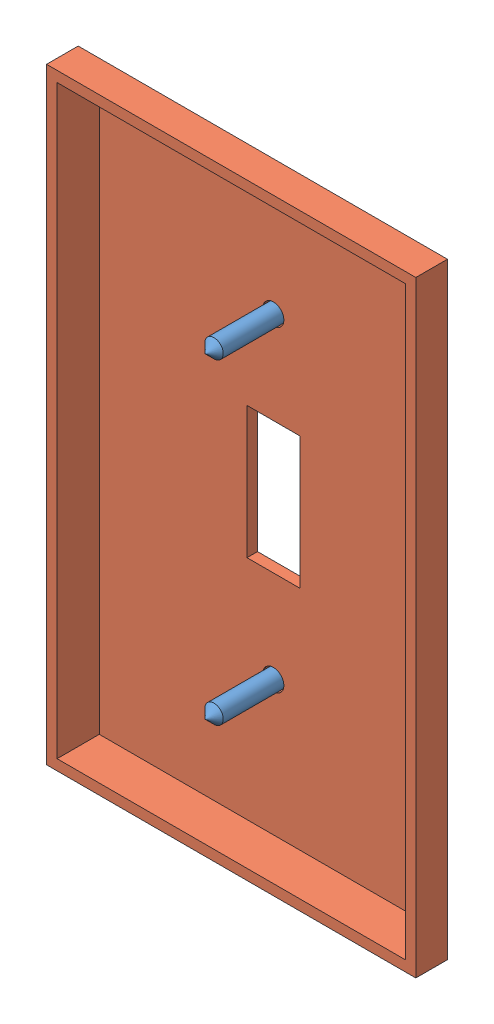
SolidWorks assembly 8.2, configuration Default. Lengths in mm.
Overall size (70 115 18.07).
3 component instances, 2 part files, 4 mates.
Components (placement in the parent):
- fastener-1: fastener [Default] at (7.1613 18.208 7.5946) size (8 8 18.07)
- exercise2.2-1: exercise2.2 [Default] at (-27.8387 -9.292 10.5946) x (1 0 0) z (0 -1 0) size (70 10 115)
- fastener-2: fastener [Default] at (7.1613 78.208 7.5946) size (8 8 18.07)
Mates (geometry in assembly coordinates):
- Concentric1: concentric anti-aligned: cylinder of exercise2.2-1 through (7.1613 78.208 4.5946) axis (0 0 1) radius 2; cylinder of fastener-2 through (7.1613 78.208 25.5946) axis (0 0 -1) radius 1.75
- Coincident1: coincident anti-aligned: plane of exercise2.2-1 through (-27.8387 -9.292 10.5946) normal (0 0 -1); plane of fastener-2 through (7.1613 78.208 10.5946) normal (0 0 1)
- Coincident2: coincident anti-aligned: plane of fastener-1 through (7.1613 18.208 10.5946) normal (0 0 1); plane of exercise2.2-1 through (-27.8387 -9.292 10.5946) normal (0 0 -1)
- Concentric2: concentric anti-aligned: cylinder of fastener-1 through (7.1613 18.208 25.5946) axis (0 0 -1) radius 1.75; cylinder of exercise2.2-1 through (7.1613 18.208 4.5946) axis (0 0 1) radius 2
